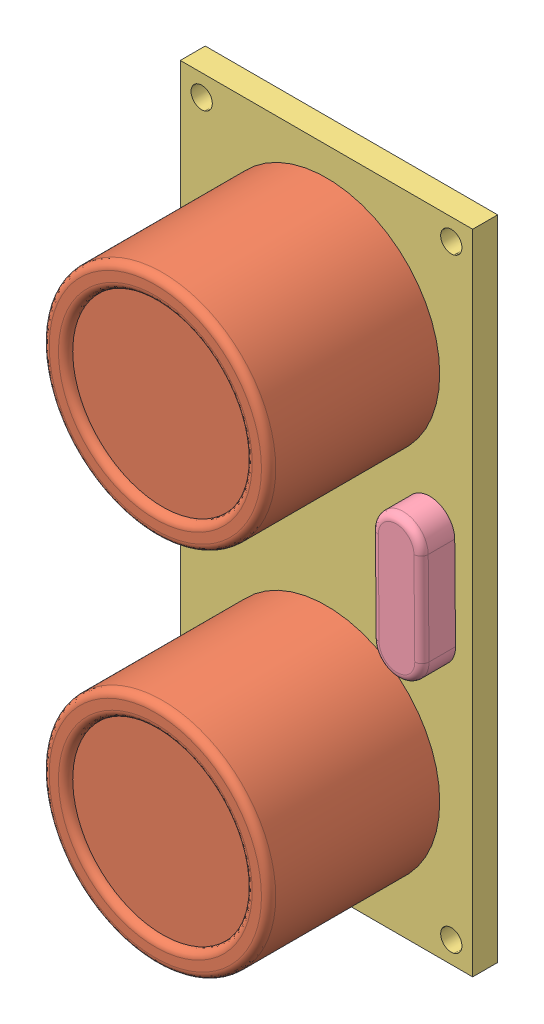
SolidWorks assembly HC SR04, configuration Default. Lengths in mm.
Overall size (24.68 45.4 17.95).
10 component instances, 6 part files, 17 mates.
Components (placement in the parent):
- SMD dioda-1: SMD dioda [Default] at (-6.5049 -8.0116 -0.9148) x (0.008727 -0.999962 0) z (0.99981 0.008725 0.017452) size (4.5 1.84 1.75)
- Transducer-2: Transducer [Default] at (0 12.76 13.25) x (1 0 0) z (0 -1 0) size (15.88 12 15.88)
- SMD dioda-2: SMD dioda [Default] at (-3.9609 -8.0389 -0.9238) x (0.008727 -0.999962 0) z (0.999924 0.008726 0.008727) size (4.5 1.84 1.75)
- PCB-2: PCB [Default] at origin size (20.5 45.4 1.75)
- Transducer-3: Transducer [Default] at (0 -13.22 13.25) x (1 0 0) z (0 -1 0) size (15.88 12 15.88)
- Crystal-1: Crystal [Default] at (7.2695 -0.013 1.4086) x (0.008727 -0.999962 0) z (0 0 1) size (10 3.5 2.7)
- IC-1: IC [Default] at (-1.5625 -14.2036 -0.8096) x (-1 0 0) z (0 -0.999962 -0.008727) size (6 1.6 8.8)
- IC-2: IC [Default] at (-1.2482 0.0887 -0.804) x (-1 0 0) z (0 -0.999962 -0.008727) size (6 1.6 8.8)
- IC-3: IC [Default] at (0.5567 14.7794 -0.8432) x (0.008727 -0.999962 0) z (0.999924 0.008726 -0.008727) size (6 1.6 8.8)
- pin-1: pin [Default] at (-7.887 0.4918 -1.0851) x (0.999962 0.008727 0) z (-0.008726 0.999924 -0.008727) size (8 7.82 10)
Mates (geometry in assembly coordinates):
- Lock2: lock: unknown of Transducer-2; unknown of Transducer-3
- Lock3: lock: unknown of Transducer-2; unknown of Transducer-3
- Lock4: lock: unknown of PCB-2; unknown of Crystal-1
- Lock5: lock: unknown of PCB-2; unknown of Transducer-3
- Lock6: lock: unknown of PCB-2; unknown of pin-1
- Lock7: lock: unknown of PCB-2; unknown of IC-1
- Lock8: lock: unknown of PCB-2; unknown of IC-2
- Lock9: lock: unknown of PCB-2; unknown of IC-3
- Lock10: lock: unknown of SMD dioda-2; unknown of PCB-2
- Lock11: lock: unknown of SMD dioda-1; unknown of PCB-2
- Coincident1: coincident anti-aligned: plane of PCB-2 through (-10.25 -22.7 1.75) normal (0 0 1); plane of Transducer-3 through (0 -13.22 1.75) normal (0 0 -1)
- Coincident2: coincident anti-aligned: plane of Transducer-2 through (0 12.76 1.75) normal (0 0 -1); plane of PCB-2 through (-10.25 -22.7 1.75) normal (0 0 1)
- Distance2: distance = 10.1 mm: cylinder of Transducer-2 through (0 12.76 13.25) axis (0 0 1) radius 7.94; cylinder of Transducer-3 through (0 -13.22 13.25) axis (0 0 1) radius 7.94
- Coincident3: coordinate: point of PCB-2
- Coincident4: coincident aligned: plane of Transducer-3 through (0 -13.22 13.25) normal (1 0 0)
- Coincident5: coincident aligned: plane of Transducer-2 through (0 12.76 13.25) normal (1 0 0)
- Distance3: distance = 2 mm aligned: cylinder of Transducer-2 through (0 12.76 13.25) axis (0 0 1) radius 7.94; plane of PCB-2 through (-10.25 22.7 1.75) normal (0 1 0)
